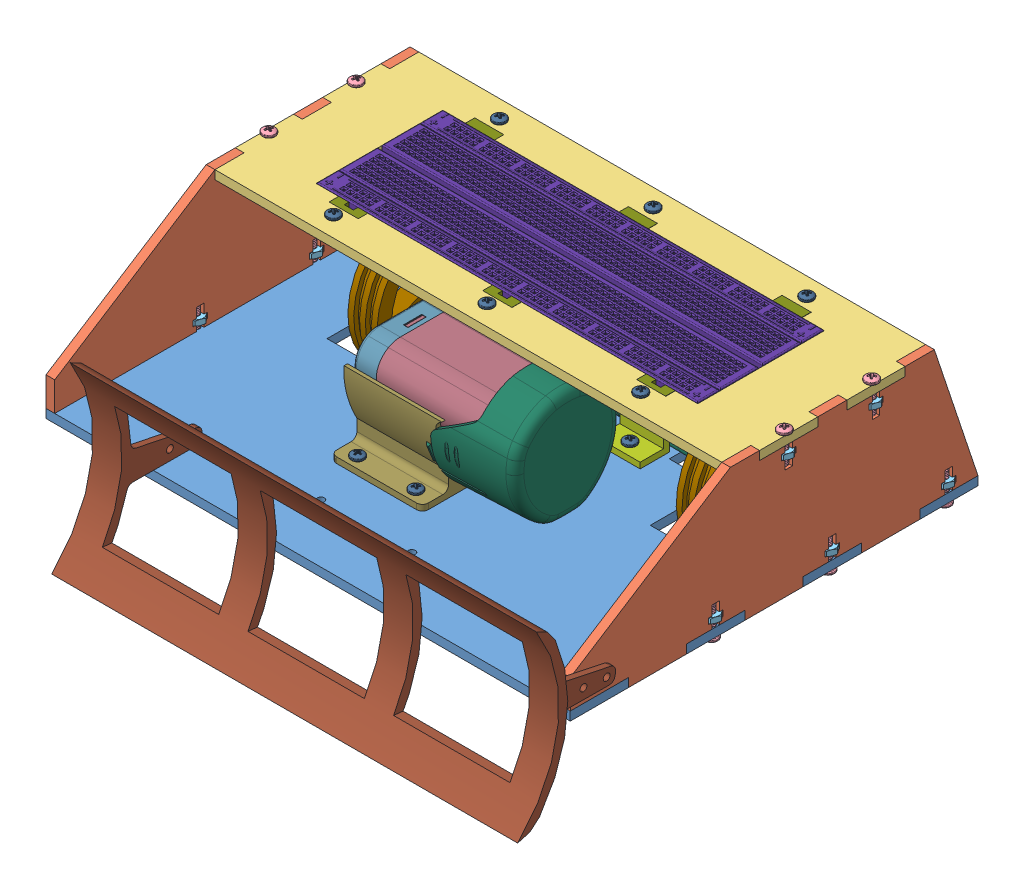
SolidWorks assembly Full Assembly, configuration Default. Lengths in mm.
Overall size (234.18 110.24 182.92).
76 component instances, 17 part files, 69 mates.
Components (placement in the parent):
- Frame Assembly-1: Frame Assembly [Default] at origin size (233.62 64.89 177.8)
  - Base Plate-1: Base Plate [Default] at (0 0 -88.9) x (-1 0 0) z (0 0 -1) size (228.6 3.81 177.8)
  - Side Plate-1: Side Plate [Default] at (-114.3 0 -88.9) size (3.81 60.96 177.8)
  - Side Plate-2: Side Plate [Default] at (110.49 0 -88.9) size (3.81 60.96 177.8)
  - Top Plate-1: Top Plate [Default] at (0 57.15 -114.3) x (-1 0 0) z (0 0 -1) size (228.6 3.81 88.9)
  - 91772A110_18-8 SS PAN HEAD PHILLIPS MACHINE SCREW-1: 91772A110_18-8 SS PAN HEAD PHILLIPS MACHINE SCREW [91772A110] at (112.395 12.7 -63.5) x (0.947469 0 0.319849) z (0 -1 0) size (5.56 5.56 14.77)
  - 91772A110_18-8 SS PAN HEAD PHILLIPS MACHINE SCREW-2: 91772A110_18-8 SS PAN HEAD PHILLIPS MACHINE SCREW [91772A110] at (112.395 48.26 -133.35) x (-0.618252 0 -0.78598) z (0 1 0) size (5.56 5.56 14.77)
  - 91772A110_18-8 SS PAN HEAD PHILLIPS MACHINE SCREW-3: 91772A110_18-8 SS PAN HEAD PHILLIPS MACHINE SCREW [91772A110] at (112.395 48.26 -95.25) x (-0.748146 0 -0.663534) z (0 1 0) size (5.56 5.56 14.77)
  - 91772A110_18-8 SS PAN HEAD PHILLIPS MACHINE SCREW-4: 91772A110_18-8 SS PAN HEAD PHILLIPS MACHINE SCREW [91772A110] at (112.395 12.7 -114.3) x (0.947469 0 0.319849) z (0 -1 0) size (5.56 5.56 14.77)
  - 91772A110_18-8 SS PAN HEAD PHILLIPS MACHINE SCREW-5: 91772A110_18-8 SS PAN HEAD PHILLIPS MACHINE SCREW [91772A110] at (112.395 12.7 -165.1) x (0.947469 0 0.319849) z (0 -1 0) size (5.56 5.56 14.77)
  - 91772A110_18-8 SS PAN HEAD PHILLIPS MACHINE SCREW-11: 91772A110_18-8 SS PAN HEAD PHILLIPS MACHINE SCREW [91772A110] at (-112.395 12.7 -165.1) x (0.947469 0 0.319849) z (0 -1 0) size (5.56 5.56 14.77)
  - 91772A110_18-8 SS PAN HEAD PHILLIPS MACHINE SCREW-12: 91772A110_18-8 SS PAN HEAD PHILLIPS MACHINE SCREW [91772A110] at (-112.395 48.26 -133.35) x (0.947469 0 0.319849) z (0 1 0) size (5.56 5.56 14.77)
  - 91772A110_18-8 SS PAN HEAD PHILLIPS MACHINE SCREW-13: 91772A110_18-8 SS PAN HEAD PHILLIPS MACHINE SCREW [91772A110] at (-112.395 12.7 -63.5) x (0.947469 0 0.319849) z (0 -1 0) size (5.56 5.56 14.77)
  - 91772A110_18-8 SS PAN HEAD PHILLIPS MACHINE SCREW-14: 91772A110_18-8 SS PAN HEAD PHILLIPS MACHINE SCREW [91772A110] at (-112.395 12.7 -114.3) x (0.947469 0 0.319849) z (0 -1 0) size (5.56 5.56 14.77)
  - 91772A110_18-8 SS PAN HEAD PHILLIPS MACHINE SCREW-15: 91772A110_18-8 SS PAN HEAD PHILLIPS MACHINE SCREW [91772A110] at (-112.395 48.26 -95.25) x (0.947469 0 0.319849) z (0 1 0) size (5.56 5.56 14.77)
  - 90480A005_LOW-STRENGTH STEEL HEX NUT-1: 90480A005_LOW-STRENGTH STEEL HEX NUT [90480A005] at (-112.395 7.5406 -165.1) x (-0.899638 0 -0.436636) z (0.436636 0 -0.899638) size (6.35 2.87 7.33)
  - 90480A005_LOW-STRENGTH STEEL HEX NUT-2: 90480A005_LOW-STRENGTH STEEL HEX NUT [90480A005] at (-112.395 7.5406 -114.3) x (0.945332 0 0.326111) z (-0.326111 0 0.945332) size (6.35 2.87 7.33)
  - 90480A005_LOW-STRENGTH STEEL HEX NUT-3: 90480A005_LOW-STRENGTH STEEL HEX NUT [90480A005] at (-112.395 53.4194 -95.25) x (0.945332 0 0.326111) z (-0.326111 0 0.945332) size (6.35 2.87 7.33)
  - 90480A005_LOW-STRENGTH STEEL HEX NUT-4: 90480A005_LOW-STRENGTH STEEL HEX NUT [90480A005] at (112.395 7.5406 -114.3) x (0.917174 0 0.398486) z (-0.398486 0 0.917174) size (6.35 2.87 7.33)
  - 90480A005_LOW-STRENGTH STEEL HEX NUT-5: 90480A005_LOW-STRENGTH STEEL HEX NUT [90480A005] at (112.395 7.5406 -63.5) x (0.945332 0 0.326111) z (-0.326111 0 0.945332) size (6.35 2.87 7.33)
  - 90480A005_LOW-STRENGTH STEEL HEX NUT-6: 90480A005_LOW-STRENGTH STEEL HEX NUT [90480A005] at (-112.395 53.4194 -133.35) x (0.945332 0 0.326111) z (-0.326111 0 0.945332) size (6.35 2.87 7.33)
  - 90480A005_LOW-STRENGTH STEEL HEX NUT-7: 90480A005_LOW-STRENGTH STEEL HEX NUT [90480A005] at (-112.395 7.5406 -63.5) x (0.945332 0 0.326111) z (-0.326111 0 0.945332) size (6.35 2.87 7.33)
  - 90480A005_LOW-STRENGTH STEEL HEX NUT-8: 90480A005_LOW-STRENGTH STEEL HEX NUT [90480A005] at (112.395 7.5406 -165.1) x (0.945332 0 0.326111) z (-0.326111 0 0.945332) size (6.35 2.87 7.33)
  - 90480A005_LOW-STRENGTH STEEL HEX NUT-9: 90480A005_LOW-STRENGTH STEEL HEX NUT [90480A005] at (112.395 53.4194 -95.25) x (0.945332 0 0.326111) z (-0.326111 0 0.945332) size (6.35 2.87 7.33)
  - 90480A005_LOW-STRENGTH STEEL HEX NUT-10: 90480A005_LOW-STRENGTH STEEL HEX NUT [90480A005] at (112.395 53.4194 -133.35) x (0.945332 0 0.326111) z (-0.326111 0 0.945332) size (6.35 2.87 7.33)
- Motor Assembly-1: Motor Assembly [Default] at (-151.2664 -161.2845 -83.6353) x (-0.147767 -0.098973 -0.984057) z (0.882818 0.435352 -0.176351) size (88.32 85.06 88.32)
  - Drive Motor-1: Drive Motor [Default] at (11.5236 110.772 167.8586) x (-0.147767 -0.445866 0.882818) z (-0.984057 -0.023044 -0.176351) size (55.9 20.6 15.6)
  - Motor Mount-1: Motor Mount [Default] at (9.6111 98.2693 179.4271) x (0.984057 0.023044 0.176351) z (0.098973 -0.894803 -0.435352) size (40.64 19.05 14.4)
  - Wheel Hub-1: Wheel Hub [Default] at (11.6773 111.2357 166.9405) x (-0.87109 -0.36404 -0.329662) z (0.468366 -0.817728 -0.334596) size (13.93 17.78 12.06)
  - Wheel-1: Wheel [Default] at (14.1169 118.5969 152.3652) x (0.841162 -0.526153 -0.124938) z (-0.147767 -0.445866 0.882818) size (63.5 63.5 12.7)
- Motor Assembly-2: Motor Assembly [Default] at (151.2664 -161.2845 -170.3647) x (0.147767 -0.098973 0.984057) z (-0.882818 0.435352 0.176351) size (88.32 85.06 88.32)
  - Drive Motor-1: Drive Motor [Default] at (11.5236 110.772 167.8586) x (-0.147767 -0.445866 0.882818) z (-0.984057 -0.023044 -0.176351) size (55.9 20.6 15.6)
  - Motor Mount-1: Motor Mount [Default] at (9.6111 98.2693 179.4271) x (0.984057 0.023044 0.176351) z (0.098973 -0.894803 -0.435352) size (40.64 19.05 14.4)
  - Wheel Hub-1: Wheel Hub [Default] at (11.6773 111.2357 166.9405) x (-0.87109 -0.36404 -0.329662) z (0.468366 -0.817728 -0.334596) size (13.93 17.78 12.06)
  - Wheel-1: Wheel [Default] at (14.1169 118.5969 152.3652) x (0.841162 -0.526153 -0.124938) z (-0.147767 -0.445866 0.882818) size (63.5 63.5 12.7)
- 91772A108_18-8 SS PAN HEAD PHILLIPS MACHINE SCREW-2: 91772A108_18-8 SS PAN HEAD PHILLIPS MACHINE SCREW [91772A108] at (28.575 -3.175 -142.24) x (-0.815676 0 -0.578509) z (0 1 0) size (5.56 5.56 11.6)
- 91772A108_18-8 SS PAN HEAD PHILLIPS MACHINE SCREW-3: 91772A108_18-8 SS PAN HEAD PHILLIPS MACHINE SCREW [91772A108] at (28.575 -3.175 -111.76) x (-0.815676 0 -0.578509) z (0 1 0) size (5.56 5.56 11.6)
- 91772A108_18-8 SS PAN HEAD PHILLIPS MACHINE SCREW-4: 91772A108_18-8 SS PAN HEAD PHILLIPS MACHINE SCREW [91772A108] at (-28.575 -3.175 -111.76) x (-0.815676 0 -0.578509) z (0 1 0) size (5.56 5.56 11.6)
- 91772A108_18-8 SS PAN HEAD PHILLIPS MACHINE SCREW-5: 91772A108_18-8 SS PAN HEAD PHILLIPS MACHINE SCREW [91772A108] at (-28.575 -3.175 -142.24) x (-0.815676 0 -0.578509) z (0 1 0) size (5.56 5.56 11.6)
- 90480A005_LOW-STRENGTH STEEL HEX NUT-1: 90480A005_LOW-STRENGTH STEEL HEX NUT [90480A005] at (-28.575 -1.1906 -111.76) x (0.940291 0 0.340373) z (-0.340373 0 0.940291) size (6.35 2.87 7.33)
- 90480A005_LOW-STRENGTH STEEL HEX NUT-2: 90480A005_LOW-STRENGTH STEEL HEX NUT [90480A005] at (-28.575 -1.1906 -142.24) x (0.940291 0 0.340373) z (-0.340373 0 0.940291) size (6.35 2.87 7.33)
- 90480A005_LOW-STRENGTH STEEL HEX NUT-3: 90480A005_LOW-STRENGTH STEEL HEX NUT [90480A005] at (28.575 -1.1906 -142.24) x (0.940291 0 0.340373) z (-0.340373 0 0.940291) size (6.35 2.87 7.33)
- 90480A005_LOW-STRENGTH STEEL HEX NUT-4: 90480A005_LOW-STRENGTH STEEL HEX NUT [90480A005] at (28.575 -1.1906 -111.76) x (0.940291 0 0.340373) z (-0.340373 0 0.940291) size (6.35 2.87 7.33)
- Plow-1: Plow [Default] at (25.4 20.8691 77.2738) x (1 0 0) z (0 0.105865 0.994381) size (203.2 76.2 48.98) (hidden)
- Battery Assembly-1: Battery Assembly [Default] at (-60.8732 -8.3132 -61.4814) x (0 0 -1) z (1 0 0) size (55.88 50.31 82.98)
  - Battery Mount-1: Battery Mount [Default] at (9.0036 39.57 13.1732) size (55.88 33 42.7)
  - Battery-1: Battery [Default] at (10.6815 38.6044 113.7732) x (-1 0.000001 0) z (0 0 -1) size (51.94 49.97 82.98)
    - battery.stp-1: battery.stp [Default] at origin size (51.94 49.97 82.98)
      - BOSCH_BATTERY_108_BODY.stp-1: BOSCH_BATTERY_108_BODY.stp [Default] at (1.6476 0.6188 12.9785) x (1 -0.000001 0) z (0 0 1) size (39.5 37.7 66)
      - BOSCH_BATTERY_108_TOP.stp-1: BOSCH_BATTERY_108_TOP.stp [Default] at (1.6476 0.6188 73.9785) x (1 -0.000001 0) z (0 0 1) size (39.5 37.02 19)
      - BOSCH_BATTERY_108_CAP2.stp-1: BOSCH_BATTERY_108_CAP2.stp [Default] at (1.6476 -0.3955 10) x (1 -0.000001 0) z (0 0 1) size (51.94 49.97 42.78)
- 91772A108_18-8 SS PAN HEAD PHILLIPS MACHINE SCREW-6: 91772A108_18-8 SS PAN HEAD PHILLIPS MACHINE SCREW [91772A108] at (-25.4 -3.175 -46.99) x (-0.065255 0 -0.997869) z (0 1 0) size (5.56 5.56 11.6)
- 91772A108_18-8 SS PAN HEAD PHILLIPS MACHINE SCREW-7: 91772A108_18-8 SS PAN HEAD PHILLIPS MACHINE SCREW [91772A108] at (0 -3.175 -93.98) x (-0.815676 0 -0.578509) z (0 1 0) size (5.56 5.56 11.6)
- 91772A108_18-8 SS PAN HEAD PHILLIPS MACHINE SCREW-8: 91772A108_18-8 SS PAN HEAD PHILLIPS MACHINE SCREW [91772A108] at (0 -3.175 -46.99) x (-0.815676 0 -0.578509) z (0 1 0) size (5.56 5.56 11.6)
- 91772A108_18-8 SS PAN HEAD PHILLIPS MACHINE SCREW-9: 91772A108_18-8 SS PAN HEAD PHILLIPS MACHINE SCREW [91772A108] at (-25.4 -3.175 -93.98) x (-0.815676 0 -0.578509) z (0 1 0) size (5.56 5.56 11.6)
- 90480A005_LOW-STRENGTH STEEL HEX NUT-5: 90480A005_LOW-STRENGTH STEEL HEX NUT [90480A005] at (-25.4 -1.1906 -46.99) x (0.966854 0 0.255328) z (-0.255328 0 0.966854) size (6.35 2.87 7.33)
- 90480A005_LOW-STRENGTH STEEL HEX NUT-6: 90480A005_LOW-STRENGTH STEEL HEX NUT [90480A005] at (-25.4 -1.1906 -93.98) x (0.940291 0 0.340373) z (-0.340373 0 0.940291) size (6.35 2.87 7.33)
- 90480A005_LOW-STRENGTH STEEL HEX NUT-7: 90480A005_LOW-STRENGTH STEEL HEX NUT [90480A005] at (0 -1.1906 -93.98) x (0.940291 0 0.340373) z (-0.340373 0 0.940291) size (6.35 2.87 7.33)
- 90480A005_LOW-STRENGTH STEEL HEX NUT-8: 90480A005_LOW-STRENGTH STEEL HEX NUT [90480A005] at (0 -1.1906 -46.99) x (0.940291 0 0.340373) z (-0.340373 0 0.940291) size (6.35 2.87 7.33)
- Breadboard Assembly-1: Breadboard Assembly [Default] at (-67.056 48.895 -114.3) size (166 12.64 81.28)
  - Breadboard Mount-1: Breadboard Mount [Default] at origin size (12.7 12.06 81.28)
  - Breadboard-1: Breadboard [Default] at (-16.0061 3.54 -27.4979) x (0 0 1) z (-1 0 0) size (57 10.1 166)
  - Breadboard Mount-3: Breadboard Mount [Default] at (66.9878 0 0) size (12.7 12.06 81.28)
  - Breadboard Mount-4: Breadboard Mount [Default] at (133.9878 0 0) size (12.7 12.06 81.28)
- 91772A108_18-8 SS PAN HEAD PHILLIPS MACHINE SCREW-10: 91772A108_18-8 SS PAN HEAD PHILLIPS MACHINE SCREW [91772A108] at (-67.056 51.435 -78.105) x (-0.802996 0 -0.595984) z (0 1 0) size (5.56 5.56 11.6)
- 91772A108_18-8 SS PAN HEAD PHILLIPS MACHINE SCREW-11: 91772A108_18-8 SS PAN HEAD PHILLIPS MACHINE SCREW [91772A108] at (-0.0682 51.435 -78.105) x (-0.815676 0 -0.578509) z (0 1 0) size (5.56 5.56 11.6)
- 91772A108_18-8 SS PAN HEAD PHILLIPS MACHINE SCREW-12: 91772A108_18-8 SS PAN HEAD PHILLIPS MACHINE SCREW [91772A108] at (66.9318 51.435 -78.105) x (-0.815676 0 -0.578509) z (0 1 0) size (5.56 5.56 11.6)
- 91772A108_18-8 SS PAN HEAD PHILLIPS MACHINE SCREW-13: 91772A108_18-8 SS PAN HEAD PHILLIPS MACHINE SCREW [91772A108] at (66.9318 51.435 -150.495) x (-0.815676 0 -0.578509) z (0 1 0) size (5.56 5.56 11.6)
- 91772A108_18-8 SS PAN HEAD PHILLIPS MACHINE SCREW-14: 91772A108_18-8 SS PAN HEAD PHILLIPS MACHINE SCREW [91772A108] at (-0.0682 51.435 -150.495) x (-0.815676 0 -0.578509) z (0 1 0) size (5.56 5.56 11.6)
- 91772A108_18-8 SS PAN HEAD PHILLIPS MACHINE SCREW-15: 91772A108_18-8 SS PAN HEAD PHILLIPS MACHINE SCREW [91772A108] at (-67.056 51.435 -150.495) x (-0.815676 0 -0.578509) z (0 1 0) size (5.56 5.56 11.6)
- 90480A005_LOW-STRENGTH STEEL HEX NUT-9: 90480A005_LOW-STRENGTH STEEL HEX NUT [90480A005] at (-67.056 53.4194 -78.105) x (0.940291 0 0.340373) z (-0.340373 0 0.940291) size (6.35 2.87 7.33)
- 90480A005_LOW-STRENGTH STEEL HEX NUT-10: 90480A005_LOW-STRENGTH STEEL HEX NUT [90480A005] at (66.9318 53.4194 -150.495) x (0.940291 0 0.340373) z (-0.340373 0 0.940291) size (6.35 2.87 7.33)
- 90480A005_LOW-STRENGTH STEEL HEX NUT-11: 90480A005_LOW-STRENGTH STEEL HEX NUT [90480A005] at (66.9318 53.4194 -78.105) x (0.601017 0 0.799236) z (-0.799236 0 0.601017) size (6.35 2.87 7.33)
- 90480A005_LOW-STRENGTH STEEL HEX NUT-12: 90480A005_LOW-STRENGTH STEEL HEX NUT [90480A005] at (-0.0682 53.4194 -78.105) x (0.601017 0 0.799236) z (-0.799236 0 0.601017) size (6.35 2.87 7.33)
- 90480A005_LOW-STRENGTH STEEL HEX NUT-13: 90480A005_LOW-STRENGTH STEEL HEX NUT [90480A005] at (-0.0682 53.4194 -150.495) x (0.940291 0 0.340373) z (-0.340373 0 0.940291) size (6.35 2.87 7.33)
- 90480A005_LOW-STRENGTH STEEL HEX NUT-14: 90480A005_LOW-STRENGTH STEEL HEX NUT [90480A005] at (-67.056 53.4194 -150.495) x (0.940291 0 0.340373) z (-0.340373 0 0.940291) size (6.35 2.87 7.33)
Mates (geometry in assembly coordinates):
- Coincident6: coincident: circle of Frame Assembly-1/Base Plate-1; circle of Motor Assembly-2/Motor Mount-1
- Coincident7: coincident: circle of Frame Assembly-1/Base Plate-1; circle of Motor Assembly-2/Motor Mount-1
- Coincident9: coincident: circle of Frame Assembly-1/Base Plate-1; circle of Motor Assembly-1/Motor Mount-1
- Coincident10: coincident: circle of Frame Assembly-1/Base Plate-1; circle of Motor Assembly-1/Motor Mount-1
- Coincident11: coincident: plane of Motor Assembly-2/Motor Mount-1 through (19.05 6.35 -137.16) normal (0 1 0); plane of 91772A108_18-8 SS PAN HEAD PHILLIPS MACHINE SCREW-2 through (28.575 6.35 -142.24) normal (0 -1 0)
- Concentric5: concentric: circle of Motor Assembly-2/Motor Mount-1; circle of 91772A108_18-8 SS PAN HEAD PHILLIPS MACHINE SCREW-2
- Coincident12: coincident: plane of Motor Assembly-2/Motor Mount-1 through (19.05 6.35 -106.68) normal (0 1 0); plane of 91772A108_18-8 SS PAN HEAD PHILLIPS MACHINE SCREW-3 through (28.575 6.35 -111.76) normal (0 -1 0)
- Concentric6: concentric: circle of Motor Assembly-2/Motor Mount-1; circle of 91772A108_18-8 SS PAN HEAD PHILLIPS MACHINE SCREW-3
- Coincident13: coincident: plane of Motor Assembly-1/Motor Mount-1 through (-19.05 6.35 -116.84) normal (0 1 0); plane of 91772A108_18-8 SS PAN HEAD PHILLIPS MACHINE SCREW-4 through (-28.575 6.35 -111.76) normal (0 -1 0)
- Concentric7: concentric: circle of Motor Assembly-1/Motor Mount-1; circle of 91772A108_18-8 SS PAN HEAD PHILLIPS MACHINE SCREW-4
- Coincident14: coincident: plane of Motor Assembly-1/Motor Mount-1 through (-19.05 6.35 -147.32) normal (0 1 0); plane of 91772A108_18-8 SS PAN HEAD PHILLIPS MACHINE SCREW-5 through (-28.575 6.35 -142.24) normal (0 -1 0)
- Concentric8: concentric: circle of Motor Assembly-1/Motor Mount-1; circle of 91772A108_18-8 SS PAN HEAD PHILLIPS MACHINE SCREW-5
- Coincident15: coincident: plane of Frame Assembly-1/Base Plate-1 through (0 0 -88.9) normal (0 -1 0); plane of 90480A005_LOW-STRENGTH STEEL HEX NUT-1 through (-30.9365 0 -114.5643) normal (0 1 0)
- Concentric9: concentric: circle of Frame Assembly-1/Base Plate-1; circle of 90480A005_LOW-STRENGTH STEEL HEX NUT-1
- Coincident16: coincident: plane of Frame Assembly-1/Base Plate-1 through (0 0 -88.9) normal (0 -1 0); plane of 90480A005_LOW-STRENGTH STEEL HEX NUT-2 through (-30.9365 0 -145.0443) normal (0 1 0)
- Concentric10: concentric: circle of Frame Assembly-1/Base Plate-1; circle of 90480A005_LOW-STRENGTH STEEL HEX NUT-2
- Coincident17: coincident: plane of Frame Assembly-1/Base Plate-1 through (0 0 -88.9) normal (0 -1 0); plane of 90480A005_LOW-STRENGTH STEEL HEX NUT-3 through (26.2135 0 -145.0443) normal (0 1 0)
- Concentric11: concentric: circle of Frame Assembly-1/Base Plate-1; circle of 90480A005_LOW-STRENGTH STEEL HEX NUT-3
- Coincident18: coincident: plane of Frame Assembly-1/Base Plate-1 through (0 0 -88.9) normal (0 -1 0); plane of 90480A005_LOW-STRENGTH STEEL HEX NUT-4 through (26.2135 0 -114.5643) normal (0 1 0)
- Concentric12: concentric: circle of Frame Assembly-1/Base Plate-1; circle of 90480A005_LOW-STRENGTH STEEL HEX NUT-4
- Coincident19: coincident: plane of Frame Assembly-1/Side Plate-2 through (114.3 0 -88.9) normal (1 0 0); plane of Plow-1 through (114.3 -11.1106 16.8196) normal (-1 0 0)
- Coincident21: coincident: circle of Frame Assembly-1/Base Plate-1; circle of Battery Assembly-1/Battery Mount-1
- Coincident22: coincident: circle of Frame Assembly-1/Base Plate-1; circle of Battery Assembly-1/Battery Mount-1
- Concentric13: concentric: circle of Battery Assembly-1/Battery Mount-1; circle of 91772A108_18-8 SS PAN HEAD PHILLIPS MACHINE SCREW-6
- Coincident23: coincident: plane of Battery Assembly-1/Battery Mount-1 through (37.0299 6.35 -70.485) normal (0 1 0); plane of 91772A108_18-8 SS PAN HEAD PHILLIPS MACHINE SCREW-6 through (-25.4 6.35 -46.99) normal (0 -1 0)
- Coincident24: coincident: plane of Battery Assembly-1/Battery Mount-1 through (37.0299 6.35 -70.485) normal (0 1 0); plane of 91772A108_18-8 SS PAN HEAD PHILLIPS MACHINE SCREW-8 through (0 6.35 -46.99) normal (0 -1 0)
- Concentric14: concentric: circle of Battery Assembly-1/Battery Mount-1; circle of 91772A108_18-8 SS PAN HEAD PHILLIPS MACHINE SCREW-8
- Coincident26: coincident: plane of Battery Assembly-1/Battery Mount-1 through (37.0299 6.35 -70.485) normal (0 1 0); plane of 91772A108_18-8 SS PAN HEAD PHILLIPS MACHINE SCREW-7 through (0 6.35 -93.98) normal (0 -1 0)
- Concentric15: concentric: circle of Battery Assembly-1/Battery Mount-1; circle of 91772A108_18-8 SS PAN HEAD PHILLIPS MACHINE SCREW-7
- Coincident27: coincident: plane of Battery Assembly-1/Battery Mount-1 through (37.0299 6.35 -70.485) normal (0 1 0); plane of 91772A108_18-8 SS PAN HEAD PHILLIPS MACHINE SCREW-9 through (-25.4 6.35 -93.98) normal (0 -1 0)
- Concentric16: concentric: circle of Battery Assembly-1/Battery Mount-1; circle of 91772A108_18-8 SS PAN HEAD PHILLIPS MACHINE SCREW-9
- Concentric17: concentric: circle of Frame Assembly-1/Base Plate-1; circle of 90480A005_LOW-STRENGTH STEEL HEX NUT-5
- Coincident28: coincident: plane of Frame Assembly-1/Base Plate-1 through (0 0 -88.9) normal (0 -1 0); plane of 90480A005_LOW-STRENGTH STEEL HEX NUT-5 through (-28.0017 0 -49.573) normal (0 1 0)
- Coincident29: coincident: plane of Frame Assembly-1/Base Plate-1 through (0 0 -88.9) normal (0 -1 0); plane of 90480A005_LOW-STRENGTH STEEL HEX NUT-8 through (-2.3615 0 -49.7943) normal (0 1 0)
- Concentric18: concentric: circle of Frame Assembly-1/Base Plate-1; circle of 90480A005_LOW-STRENGTH STEEL HEX NUT-8
- Coincident30: coincident: plane of Frame Assembly-1/Base Plate-1 through (0 0 -88.9) normal (0 -1 0); plane of 90480A005_LOW-STRENGTH STEEL HEX NUT-6 through (-27.7615 0 -96.7843) normal (0 1 0)
- Concentric19: concentric: circle of Frame Assembly-1/Base Plate-1; circle of 90480A005_LOW-STRENGTH STEEL HEX NUT-6
- Coincident31: coincident: plane of Frame Assembly-1/Base Plate-1 through (0 0 -88.9) normal (0 -1 0); plane of 90480A005_LOW-STRENGTH STEEL HEX NUT-7 through (-2.3615 0 -96.7843) normal (0 1 0)
- Concentric20: concentric: circle of Frame Assembly-1/Base Plate-1; circle of 90480A005_LOW-STRENGTH STEEL HEX NUT-7
- Coincident33: coincident: plane of Frame Assembly-1 through (0 0 0) normal (0 1 0); plane of assembly through (0 0 0) normal (0 1 0)
- Coincident34: coincident: plane of Frame Assembly-1 through (0 0 0) normal (1 0 0); plane of assembly through (0 0 0) normal (1 0 0)
- Coincident35: coincident: plane of Frame Assembly-1 through (0 0 0) normal (0 0 1); plane of assembly through (0 0 0) normal (0 0 1)
- Coincident40: coincident: plane of Frame Assembly-1/Top Plate-1 through (0 57.15 -114.3) normal (0 -1 0); plane of Breadboard Assembly-1/Breadboard Mount-4 through (66.9318 57.15 -114.3) normal (0 1 0)
- Coincident41: coincident: circle of Frame Assembly-1/Top Plate-1; cylinder of Breadboard Assembly-1/Breadboard Mount-1 through (-67.056 54.61 -78.105) axis (0 1 0) radius 1.524
- Concentric21: concentric: circle of Frame Assembly-1/Top Plate-1; cylinder of Breadboard Assembly-1/Breadboard Mount-1 through (-67.056 54.61 -150.495) axis (0 1 0) radius 1.524
- Concentric22: concentric: circle of Breadboard Assembly-1/Breadboard Mount-1; circle of 91772A108_18-8 SS PAN HEAD PHILLIPS MACHINE SCREW-10
- Coincident43: coincident: plane of Frame Assembly-1/Top Plate-1 through (0 60.96 -114.3) normal (0 1 0); plane of 91772A108_18-8 SS PAN HEAD PHILLIPS MACHINE SCREW-10 through (-67.056 60.96 -78.105) normal (0 -1 0)
- Coincident44: coincident: plane of Frame Assembly-1/Top Plate-1 through (0 60.96 -114.3) normal (0 1 0); plane of 91772A108_18-8 SS PAN HEAD PHILLIPS MACHINE SCREW-11 through (-0.0682 60.96 -78.105) normal (0 -1 0)
- Concentric23: concentric: circle of Breadboard Assembly-1/Breadboard Mount-3; circle of 91772A108_18-8 SS PAN HEAD PHILLIPS MACHINE SCREW-11
- Coincident46: coincident: plane of Frame Assembly-1/Top Plate-1 through (0 60.96 -114.3) normal (0 1 0); plane of 91772A108_18-8 SS PAN HEAD PHILLIPS MACHINE SCREW-12 through (66.9318 60.96 -78.105) normal (0 -1 0)
- Concentric24: concentric: circle of Breadboard Assembly-1/Breadboard Mount-4; circle of 91772A108_18-8 SS PAN HEAD PHILLIPS MACHINE SCREW-12
- Coincident47: coincident: plane of Frame Assembly-1/Top Plate-1 through (0 60.96 -114.3) normal (0 1 0); plane of 91772A108_18-8 SS PAN HEAD PHILLIPS MACHINE SCREW-13 through (66.9318 60.96 -150.495) normal (0 -1 0)
- Concentric25: concentric: circle of Breadboard Assembly-1/Breadboard Mount-4; circle of 91772A108_18-8 SS PAN HEAD PHILLIPS MACHINE SCREW-13
- Coincident48: coincident: plane of Frame Assembly-1/Top Plate-1 through (0 60.96 -114.3) normal (0 1 0); plane of 91772A108_18-8 SS PAN HEAD PHILLIPS MACHINE SCREW-14 through (-0.0682 60.96 -150.495) normal (0 -1 0)
- Concentric26: concentric: circle of Breadboard Assembly-1/Breadboard Mount-3; circle of 91772A108_18-8 SS PAN HEAD PHILLIPS MACHINE SCREW-14
- Coincident49: coincident: plane of Frame Assembly-1/Top Plate-1 through (0 60.96 -114.3) normal (0 1 0); plane of 91772A108_18-8 SS PAN HEAD PHILLIPS MACHINE SCREW-15 through (-67.056 60.96 -150.495) normal (0 -1 0)
- Concentric27: concentric: circle of Breadboard Assembly-1/Breadboard Mount-1; circle of 91772A108_18-8 SS PAN HEAD PHILLIPS MACHINE SCREW-15
- Coincident51: coincident: plane of Breadboard Assembly-1/Breadboard Mount-4 through (66.9318 54.61 -114.3) normal (0 -1 0); plane of 90480A005_LOW-STRENGTH STEEL HEX NUT-11 through (66.4886 54.61 -81.7443) normal (0 1 0)
- Concentric28: concentric: circle of 91772A108_18-8 SS PAN HEAD PHILLIPS MACHINE SCREW-12; circle of 90480A005_LOW-STRENGTH STEEL HEX NUT-11
- Coincident52: coincident: plane of Breadboard Assembly-1/Breadboard Mount-3 through (-0.0682 54.61 -114.3) normal (0 -1 0); plane of 90480A005_LOW-STRENGTH STEEL HEX NUT-12 through (-0.5114 54.61 -81.7443) normal (0 1 0)
- Concentric29: concentric: circle of 91772A108_18-8 SS PAN HEAD PHILLIPS MACHINE SCREW-11; circle of 90480A005_LOW-STRENGTH STEEL HEX NUT-12
- Coincident53: coincident: plane of Breadboard Assembly-1/Breadboard Mount-1 through (-67.056 54.61 -114.3) normal (0 -1 0); plane of 90480A005_LOW-STRENGTH STEEL HEX NUT-9 through (-69.4175 54.61 -80.9093) normal (0 1 0)
- Concentric30: concentric: circle of 91772A108_18-8 SS PAN HEAD PHILLIPS MACHINE SCREW-10; circle of 90480A005_LOW-STRENGTH STEEL HEX NUT-9
- Coincident54: coincident: plane of Breadboard Assembly-1/Breadboard Mount-4 through (66.9318 54.61 -114.3) normal (0 -1 0); plane of 90480A005_LOW-STRENGTH STEEL HEX NUT-10 through (64.5703 54.61 -153.2993) normal (0 1 0)
- Concentric31: concentric: circle of Breadboard Assembly-1/Breadboard Mount-4; circle of 90480A005_LOW-STRENGTH STEEL HEX NUT-10
- Coincident56: coincident: plane of Breadboard Assembly-1/Breadboard Mount-3 through (-0.0682 54.61 -114.3) normal (0 -1 0); plane of 90480A005_LOW-STRENGTH STEEL HEX NUT-13 through (-2.4297 54.61 -153.2993) normal (0 1 0)
- Concentric32: concentric: circle of Breadboard Assembly-1/Breadboard Mount-3; circle of 90480A005_LOW-STRENGTH STEEL HEX NUT-13
- Coincident57: coincident: plane of Breadboard Assembly-1/Breadboard Mount-1 through (-67.056 54.61 -114.3) normal (0 -1 0); plane of 90480A005_LOW-STRENGTH STEEL HEX NUT-14 through (-69.4175 54.61 -153.2993) normal (0 1 0)
- Concentric33: concentric: circle of Breadboard Assembly-1/Breadboard Mount-1; circle of 90480A005_LOW-STRENGTH STEEL HEX NUT-14
